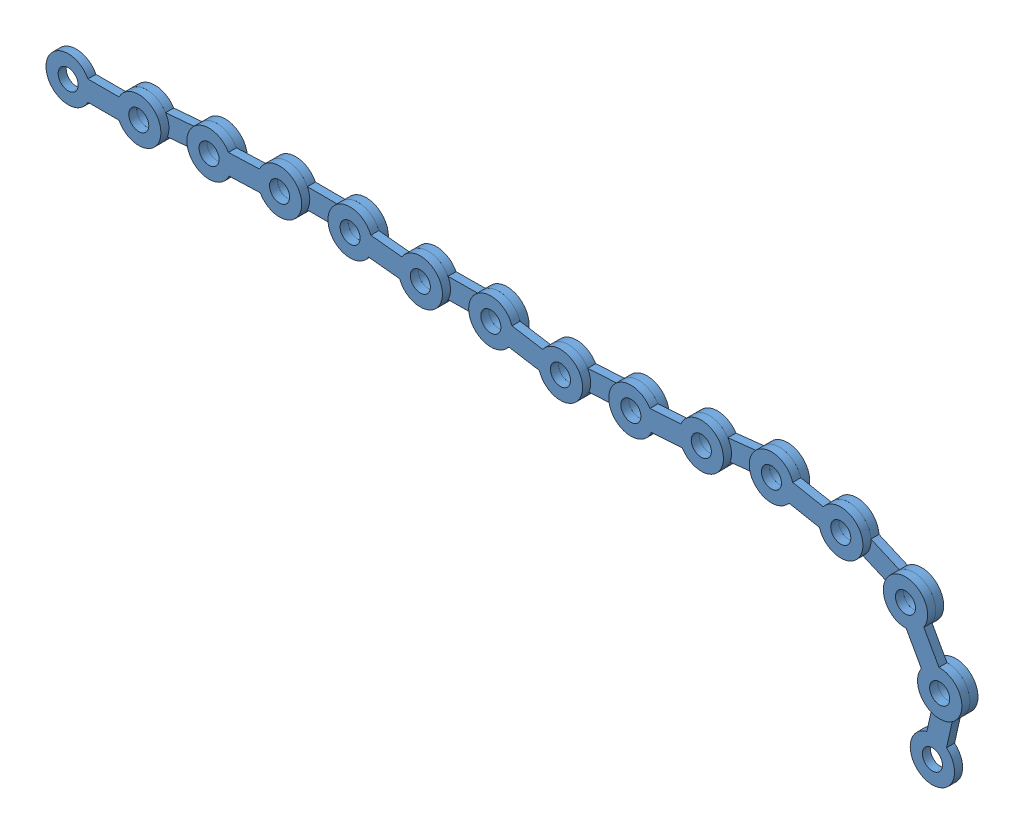
SolidWorks assembly chain, configuration Default. Lengths in mm.
Overall size (444.12 97.37 8).
14 component instances, 1 part files, 26 mates.
Components (placement in the parent):
- chainPart-1: chainPart [Default] at (92.9067 33.2306 9.9294) size (45 10 4)
- chainPart-2: chainPart [Default] at (127.9067 33.2306 5.9294) x (0.99643 0.084419 0) z (0 0 1) size (45 10 4)
- chainPart-3: chainPart [Default] at (162.7817 36.1852 9.9294) x (0.999358 0.03582 0) z (0 0 1) size (45 10 4)
- chainPart-4: chainPart [Default] at (197.7593 37.4389 5.9294) x (0.999994 -0.003474 0) z (0 0 1) size (45 10 4)
- chainPart-5: chainPart [Default] at (232.7591 37.3173 9.9294) x (0.994631 -0.103489 0) z (0 0 1) size (45 10 4)
- chainPart-6: chainPart [Default] at (267.5711 33.6952 5.9294) x (0.999959 0.009082 0) z (0 0 1) size (45 10 4)
- chainPart-7: chainPart [Default] at (302.5697 34.0131 9.9294) x (0.986781 -0.162057 0) z (0 0 1) size (45 10 4)
- chainPart-8: chainPart [Default] at (337.107 28.3411 5.9294) x (0.99823 0.059469 0) z (0 0 1) size (45 10 4)
- chainPart-9: chainPart [Default] at (372.0451 30.4225 9.9294) x (0.997633 0.06876 0) z (0 0 1) size (45 10 4)
- chainPart-10: chainPart [Default] at (406.9623 32.8291 5.9294) x (0.99408 0.108649 0) z (0 0 1) size (45 10 4)
- chainPart-11: chainPart [Default] at (441.7551 36.6318 9.9294) x (0.982626 -0.185597 0) z (0 0 1) size (45 10 4)
- chainPart-12: chainPart [Default] at (476.147 30.1359 5.9294) x (0.916872 -0.399181 0) z (0 0 1) size (45 10 4)
- chainPart-13: chainPart [Default] at (508.2375 16.1646 9.9294) x (0.48532 -0.874336 0) z (0 0 1) size (45 10 4)
- chainPart-14: chainPart [Default] at (525.2237 -14.4372 5.9294) x (-0.217955 -0.975959 0) z (0 0 1) size (45 10 4)
Mates (geometry in assembly coordinates):
- Concentric1: concentric aligned: cylinder of chainPart-1 through (127.9067 33.2306 13.9294) axis (0 0 -1) radius 2.5; cylinder of chainPart-2 through (127.9067 33.2306 9.9294) axis (0 0 -1) radius 2.5
- Coincident1: coincident anti-aligned: plane of chainPart-1 through (92.9067 33.2306 9.9294) normal (0 0 -1); plane of chainPart-2 through (127.9067 33.2306 9.9294) normal (0 0 1)
- Concentric2: concentric aligned: cylinder of chainPart-2 through (162.7817 36.1852 9.9294) axis (0 0 -1) radius 2.5; cylinder of chainPart-3 through (162.7817 36.1852 13.9294) axis (0 0 -1) radius 2.5
- Coincident2: coincident anti-aligned: plane of chainPart-2 through (127.9067 33.2306 9.9294) normal (0 0 1); plane of chainPart-3 through (162.7817 36.1852 9.9294) normal (0 0 -1)
- Concentric3: concentric aligned: cylinder of chainPart-3 through (197.7593 37.4389 13.9294) axis (0 0 -1) radius 2.5; cylinder of chainPart-4 through (197.7593 37.4389 9.9294) axis (0 0 -1) radius 2.5
- Concentric4: concentric aligned: cylinder of chainPart-4 through (232.7591 37.3173 9.9294) axis (0 0 -1) radius 2.5; cylinder of chainPart-5 through (232.7591 37.3173 13.9294) axis (0 0 -1) radius 2.5
- Concentric5: concentric aligned: cylinder of chainPart-5 through (267.5711 33.6952 13.9294) axis (0 0 -1) radius 2.5; cylinder of chainPart-6 through (267.5711 33.6952 9.9294) axis (0 0 -1) radius 2.5
- Concentric6: concentric aligned: cylinder of chainPart-6 through (302.5697 34.0131 9.9294) axis (0 0 -1) radius 2.5; cylinder of chainPart-7 through (302.5697 34.0131 13.9294) axis (0 0 -1) radius 2.5
- Concentric7: concentric aligned: cylinder of chainPart-7 through (337.107 28.3411 13.9294) axis (0 0 -1) radius 2.5; cylinder of chainPart-8 through (337.107 28.3411 9.9294) axis (0 0 -1) radius 2.5
- Concentric8: concentric aligned: cylinder of chainPart-8 through (372.0451 30.4225 9.9294) axis (0 0 -1) radius 2.5; cylinder of chainPart-9 through (372.0451 30.4225 13.9294) axis (0 0 -1) radius 2.5
- Concentric9: concentric aligned: cylinder of chainPart-9 through (406.9623 32.8291 13.9294) axis (0 0 -1) radius 2.5; cylinder of chainPart-10 through (406.9623 32.8291 9.9294) axis (0 0 -1) radius 2.5
- Concentric10: concentric aligned: cylinder of chainPart-10 through (441.7551 36.6318 9.9294) axis (0 0 -1) radius 2.5; cylinder of chainPart-11 through (441.7551 36.6318 13.9294) axis (0 0 -1) radius 2.5
- Coincident3: coincident anti-aligned: plane of chainPart-3 through (162.7817 36.1852 9.9294) normal (0 0 -1); plane of chainPart-4 through (197.7593 37.4389 9.9294) normal (0 0 1)
- Coincident4: coincident anti-aligned: plane of chainPart-4 through (197.7593 37.4389 9.9294) normal (0 0 1); plane of chainPart-5 through (232.7591 37.3173 9.9294) normal (0 0 -1)
- Coincident5: coincident anti-aligned: plane of chainPart-5 through (232.7591 37.3173 9.9294) normal (0 0 -1); plane of chainPart-6 through (267.5711 33.6952 9.9294) normal (0 0 1)
- Coincident6: coincident anti-aligned: plane of chainPart-6 through (267.5711 33.6952 9.9294) normal (0 0 1); plane of chainPart-7 through (302.5697 34.0131 9.9294) normal (0 0 -1)
- Coincident7: coincident anti-aligned: plane of chainPart-7 through (302.5697 34.0131 9.9294) normal (0 0 -1); plane of chainPart-8 through (337.107 28.3411 9.9294) normal (0 0 1)
- Coincident8: coincident anti-aligned: plane of chainPart-8 through (337.107 28.3411 9.9294) normal (0 0 1); plane of chainPart-9 through (372.0451 30.4225 9.9294) normal (0 0 -1)
- Coincident9: coincident anti-aligned: plane of chainPart-9 through (372.0451 30.4225 9.9294) normal (0 0 -1); plane of chainPart-10 through (406.9623 32.8291 9.9294) normal (0 0 1)
- Coincident10: coincident anti-aligned: plane of chainPart-10 through (406.9623 32.8291 9.9294) normal (0 0 1); plane of chainPart-11 through (441.7551 36.6318 9.9294) normal (0 0 -1)
- Concentric11: concentric aligned: cylinder of chainPart-11 through (476.147 30.1359 13.9294) axis (0 0 -1) radius 2.5; cylinder of chainPart-12 through (476.147 30.1359 9.9294) axis (0 0 -1) radius 2.5
- Coincident11: coincident anti-aligned: plane of chainPart-11 through (441.7551 36.6318 9.9294) normal (0 0 -1); plane of chainPart-12 through (476.147 30.1359 9.9294) normal (0 0 1)
- Concentric12: concentric aligned: cylinder of chainPart-12 through (508.2375 16.1646 9.9294) axis (0 0 -1) radius 2.5; cylinder of chainPart-13 through (508.2375 16.1646 13.9294) axis (0 0 -1) radius 2.5
- Coincident12: coincident anti-aligned: plane of chainPart-12 through (476.147 30.1359 9.9294) normal (0 0 1); plane of chainPart-13 through (508.2375 16.1646 9.9294) normal (0 0 -1)
- Coincident13: coincident anti-aligned: circle of chainPart-13; cylinder of chainPart-14 through (525.2237 -14.4372 9.9294) axis (0 0 -1) radius 2.5
- Coincident14: coincident anti-aligned: plane of chainPart-13 through (508.2375 16.1646 9.9294) normal (0 0 -1); plane of chainPart-14 through (525.2237 -14.4372 9.9294) normal (0 0 1)
